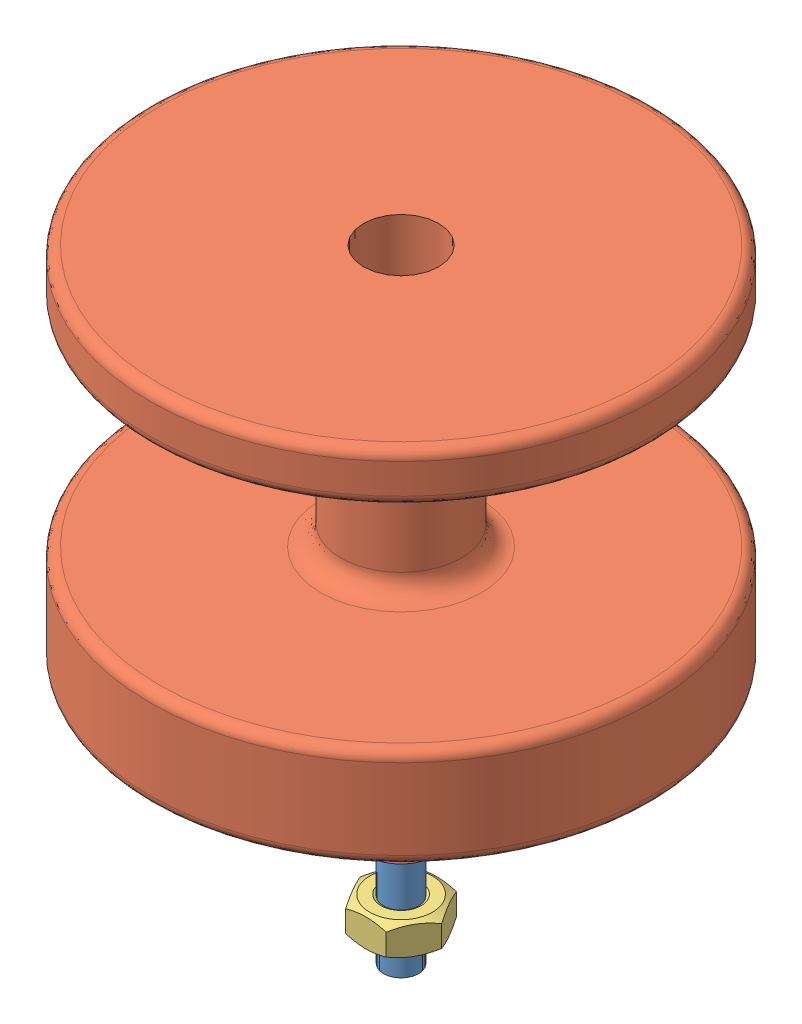
SolidWorks assembly 承重轮装配体, configuration 默认. Lengths in mm.
Overall size (50 62 50).
5 component instances, 5 part files, 8 mates.
Components (placement in the parent):
- 半牙螺丝M4 45-1: 半牙螺丝M4 45 [默认] at (-4.3383 47.1056 1.5695) size (7 49 7)
- 承重轮-1: 承重轮 [默认] at (-4.3383 53.1056 1.5695) size (50 36 50)
- hex nuts, style 1-grades ab gb-1: hex nuts, style 1-grades ab gb [GB_FASTENER_NUT_SNAB1 M4-N] at (-4.3383 33.1056 1.5695) x (1 0 0) z (0 1 0) size (8.08 7 3.2)
- 锁紧螺丝-1: 锁紧螺丝 [默认] at (-4.3383 43.1056 1.5695) x (0.837169 0 0.546944) z (0.546944 0 -0.837169) size (7.58 5 7.59)
- 承重轮_01_01-1: 承重轮_01_01 [默认] at (-4.3383 53.1056 1.5695) x (-0.837169 0 -0.546944) z (-0.546944 0 0.837169) size (12 10 12)
Mates (geometry in assembly coordinates):
- 重合1: coincident: plane of assembly; plane of assembly; plane of 半牙螺丝M4 45-1 through (-4.3383 72.1056 1.5695) normal (0 -1 0); plane of 承重轮-1 through (-4.3383 72.1056 1.5695) normal (0 1 0)
- 同心2: concentric: cylinder of assembly; cylinder of assembly; cylinder of 半牙螺丝M4 45-1 through (-4.3383 27.1056 1.5695) axis (0 1 0) radius 1.75; cylinder of hex nuts, style 1-grades ab gb-1 through (-4.3383 29.9056 1.5695) axis (0 1 0) radius 1.621
- 同心3: concentric: cylinder of assembly; cylinder of assembly; cylinder of 半牙螺丝M4 45-1 through (-4.3383 27.1056 1.5695) axis (0 1 0) radius 1.75; cylinder of 锁紧螺丝-1 through (-4.3383 38.1056 1.5695) axis (0 1 0) radius 2
- 同心4: concentric: cylinder of assembly; cylinder of assembly; cylinder of 半牙螺丝M4 45-1 through (-4.3383 27.1056 1.5695) axis (0 1 0) radius 1.75; cylinder of 承重轮-1 through (-4.3383 100.1056 1.5695) axis (0 -1 0) radius 2
- 距离1: distance = 5 mm: plane of assembly; plane of assembly; plane of 锁紧螺丝-1 through (-4.3383 38.1056 1.5695) normal (0 -1 0); plane of hex nuts, style 1-grades ab gb-1 through (-0.2968 33.1056 1.5695) normal (0 1 0)
- 重合3: coincident: plane of assembly; plane of assembly; plane of 承重轮-1 through (-4.3383 53.1056 1.5695) normal (0 -1 0); plane of 承重轮_01_01-1 through (-4.3383 53.1056 1.5695) normal (0 1 0)
- 同心5: concentric: cylinder of assembly; cylinder of assembly; cylinder of 半牙螺丝M4 45-1 through (-4.3383 72.1056 1.5695) axis (0 -1 0) radius 2; cylinder of 承重轮_01_01-1 through (-4.3383 43.1056 1.5695) axis (0 1 0) radius 2.45
- 重合4: coincident: plane of assembly; plane of assembly; plane of 锁紧螺丝-1 through (-4.3383 43.1056 1.5695) normal (0 1 0); plane of 承重轮_01_01-1 through (-4.3383 43.1056 1.5695) normal (0 -1 0)
